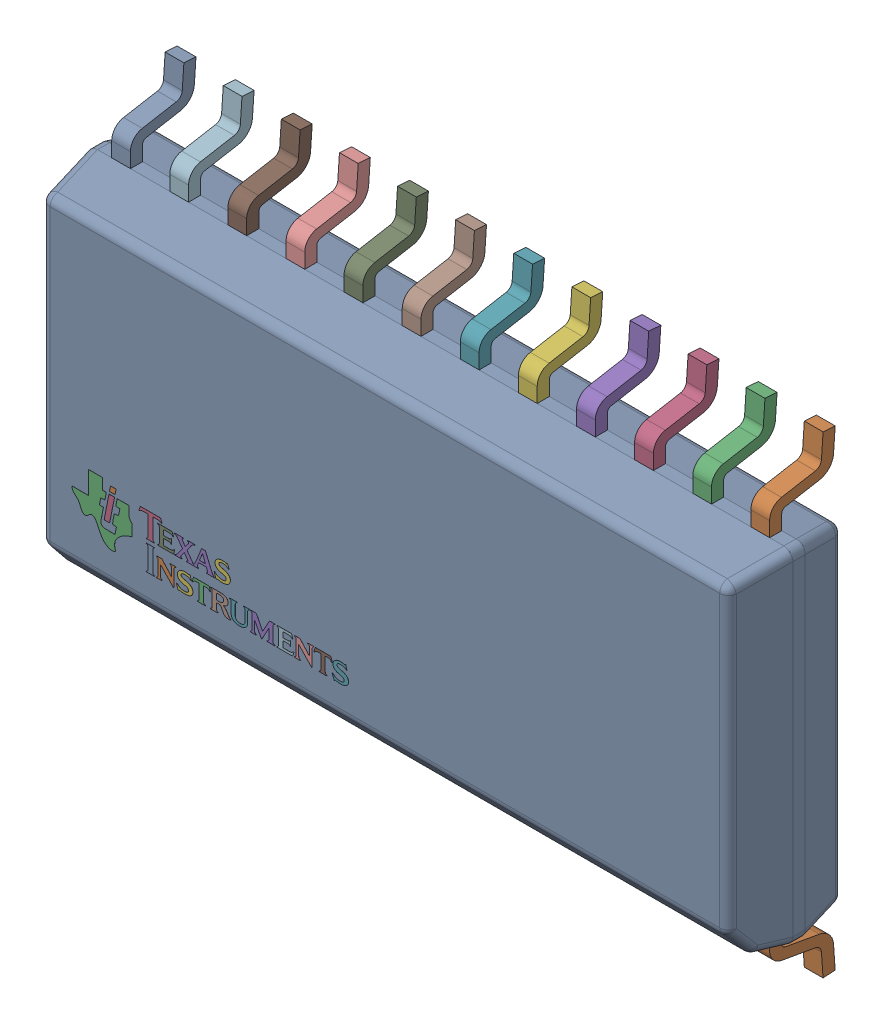
SolidWorks assembly U8, configuration Défaut. Lengths in mm.
Overall size (15.4 10.34 2.65).
28 component instances, 4 part files, 0 mates.
Components (placement in the parent):
- IC_Texas_Instruments_CD74HC4067M96_eec-1: IC_Texas_Instruments_CD74HC4067M96_eec [Défaut] at (28.875 0 0) x (0 -1 0) z (0 0 1) size (10.34 15.4 2.65)
  - BODY-SO-1: BODY-SO [Défaut] at (0 0 1.0825) x (0 1 0) z (1 0 0) size (15.4 2.45 7.5)
  - LEAD-SO-1: LEAD-SO [Défaut] at (4.315 6.985 0.25) x (0 1 0) z (1 0 0) size (0.41 1.43 1.42)
  - LEAD-SO-2: LEAD-SO [Défaut] at (4.315 5.715 0.25) x (0 1 0) z (1 0 0) size (0.41 1.43 1.42)
  - LEAD-SO-3: LEAD-SO [Défaut] at (4.315 4.445 0.25) x (0 1 0) z (1 0 0) size (0.41 1.43 1.42)
  - LEAD-SO-4: LEAD-SO [Défaut] at (4.315 3.175 0.25) x (0 1 0) z (1 0 0) size (0.41 1.43 1.42)
  - LEAD-SO-5: LEAD-SO [Défaut] at (4.315 1.905 0.25) x (0 1 0) z (1 0 0) size (0.41 1.43 1.42)
  - LEAD-SO-6: LEAD-SO [Défaut] at (4.315 0.635 0.25) x (0 1 0) z (1 0 0) size (0.41 1.43 1.42)
  - LEAD-SO-7: LEAD-SO [Défaut] at (4.315 -0.635 0.25) x (0 1 0) z (1 0 0) size (0.41 1.43 1.42)
  - LEAD-SO-8: LEAD-SO [Défaut] at (4.315 -1.905 0.25) x (0 1 0) z (1 0 0) size (0.41 1.43 1.42)
  - LEAD-SO-9: LEAD-SO [Défaut] at (4.315 -3.175 0.25) x (0 1 0) z (1 0 0) size (0.41 1.43 1.42)
  - LEAD-SO-10: LEAD-SO [Défaut] at (4.315 -4.445 0.25) x (0 1 0) z (1 0 0) size (0.41 1.43 1.42)
  - LEAD-SO-11: LEAD-SO [Défaut] at (4.315 -5.715 0.25) x (0 1 0) z (1 0 0) size (0.41 1.43 1.42)
  - LEAD-SO-12: LEAD-SO [Défaut] at (4.315 -6.985 0.25) x (0 1 0) z (1 0 0) size (0.41 1.43 1.42)
  - LEAD-SO-13: LEAD-SO [Défaut] at (-4.315 6.985 0.25) x (0 -1 0) z (-1 0 0) size (0.41 1.43 1.42)
  - LEAD-SO-14: LEAD-SO [Défaut] at (-4.315 5.715 0.25) x (0 -1 0) z (-1 0 0) size (0.41 1.43 1.42)
  - LEAD-SO-15: LEAD-SO [Défaut] at (-4.315 4.445 0.25) x (0 -1 0) z (-1 0 0) size (0.41 1.43 1.42)
  - LEAD-SO-16: LEAD-SO [Défaut] at (-4.315 3.175 0.25) x (0 -1 0) z (-1 0 0) size (0.41 1.43 1.42)
  - LEAD-SO-17: LEAD-SO [Défaut] at (-4.315 1.905 0.25) x (0 -1 0) z (-1 0 0) size (0.41 1.43 1.42)
  - LEAD-SO-18: LEAD-SO [Défaut] at (-4.315 0.635 0.25) x (0 -1 0) z (-1 0 0) size (0.41 1.43 1.42)
  - LEAD-SO-19: LEAD-SO [Défaut] at (-4.315 -0.635 0.25) x (0 -1 0) z (-1 0 0) size (0.41 1.43 1.42)
  - LEAD-SO-20: LEAD-SO [Défaut] at (-4.315 -1.905 0.25) x (0 -1 0) z (-1 0 0) size (0.41 1.43 1.42)
  - LEAD-SO-21: LEAD-SO [Défaut] at (-4.315 -3.175 0.25) x (0 -1 0) z (-1 0 0) size (0.41 1.43 1.42)
  - LEAD-SO-22: LEAD-SO [Défaut] at (-4.315 -4.445 0.25) x (0 -1 0) z (-1 0 0) size (0.41 1.43 1.42)
  - LEAD-SO-23: LEAD-SO [Défaut] at (-4.315 -5.715 0.25) x (0 -1 0) z (-1 0 0) size (0.41 1.43 1.42)
  - LEAD-SO-24: LEAD-SO [Défaut] at (-4.315 -6.985 0.25) x (0 -1 0) z (-1 0 0) size (0.41 1.43 1.42)
  - Texas Logo Yury-1: Texas Logo Yury [Défaut] at (2.174 -7.1221 2.551) x (0 1 0) z (0 0 1) size (1.32 1.29 0.11)
  - Texas Logo Yury - Copy-1: Texas Logo Yury - Copy [Défaut] at (2.0641 -7.1534 2.551) x (0 1 0) z (0 0 1) size (4.61 1.2 0.1)
